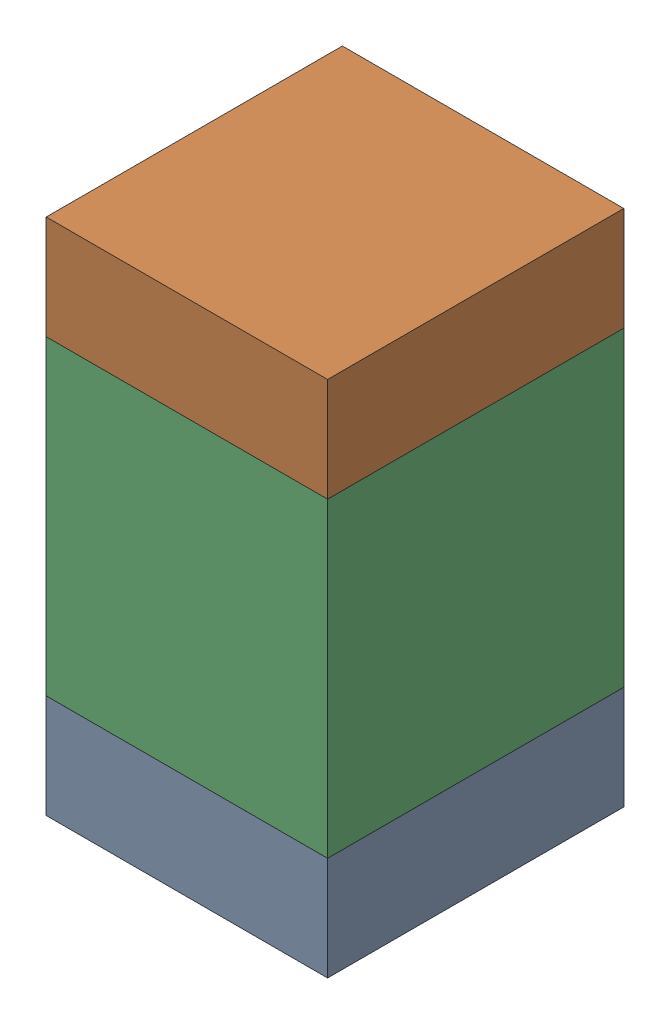
SolidWorks assembly C3-1, configuration Default. Lengths in mm.
Overall size (0.95 1.75 1).
6 component instances, 2 part files, 0 mates.
Components (placement in the parent):
- 959208664-1-1: 959208664-1 [Default] at (146.558 83.0961 0) size (0.95 0.35 1)
  - Extruded-45-1: Extruded-45 [Default] at origin size (0.95 0.35 1)
- 959208664-1-2: 959208664-1 [Default] at (146.558 84.4961 0) size (0.95 0.35 1)
  - Extruded-45-1: Extruded-45 [Default] at origin size (0.95 0.35 1)
- 959208528-1-1: 959208528-1 [Default] at (146.558 83.7961 0) size (0.95 1.05 1)
  - Extruded-46-1: Extruded-46 [Default] at origin size (0.95 1.05 1)
